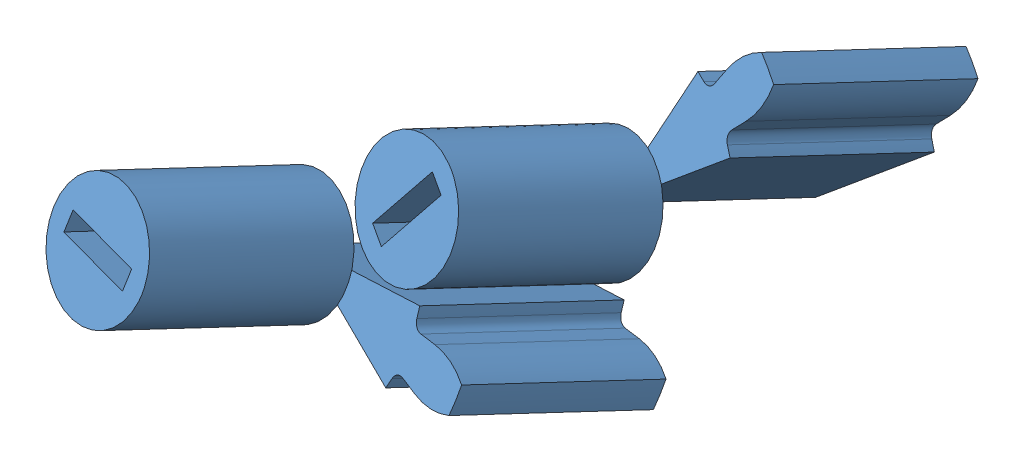
SolidWorks assembly BaseGearAssembly, configuration Default. Lengths in mm.
Overall size (30.58 29.78 25.52).
2 component instances, 1 part files, 2 mates.
Components (placement in the parent):
- BaseGear-1: BaseGear [Default] at (-15.1131 3.099 16.0201) x (0.975004 -0.091078 0.202662) z (-0.158445 0.354433 0.92156) size (13.5 6 20)
- BaseGear-2: BaseGear [Default] at (0.3438 12.2816 15.146) x (0.588726 0.7832 -0.2) z (-0.158445 0.354433 0.92156) size (13.5 6 20)
Mates (geometry in assembly coordinates):
- Distance2: distance = 18 mm: line of BaseGear-2 through (-1.2407 15.8259 24.3616) axis (0.158445 -0.354433 -0.92156); line of BaseGear-1 through (-16.6976 6.6433 25.2357) axis (0.158445 -0.354433 -0.92156)
- Tangent2: tangent: circle of BaseGear-1; circle of BaseGear-2
